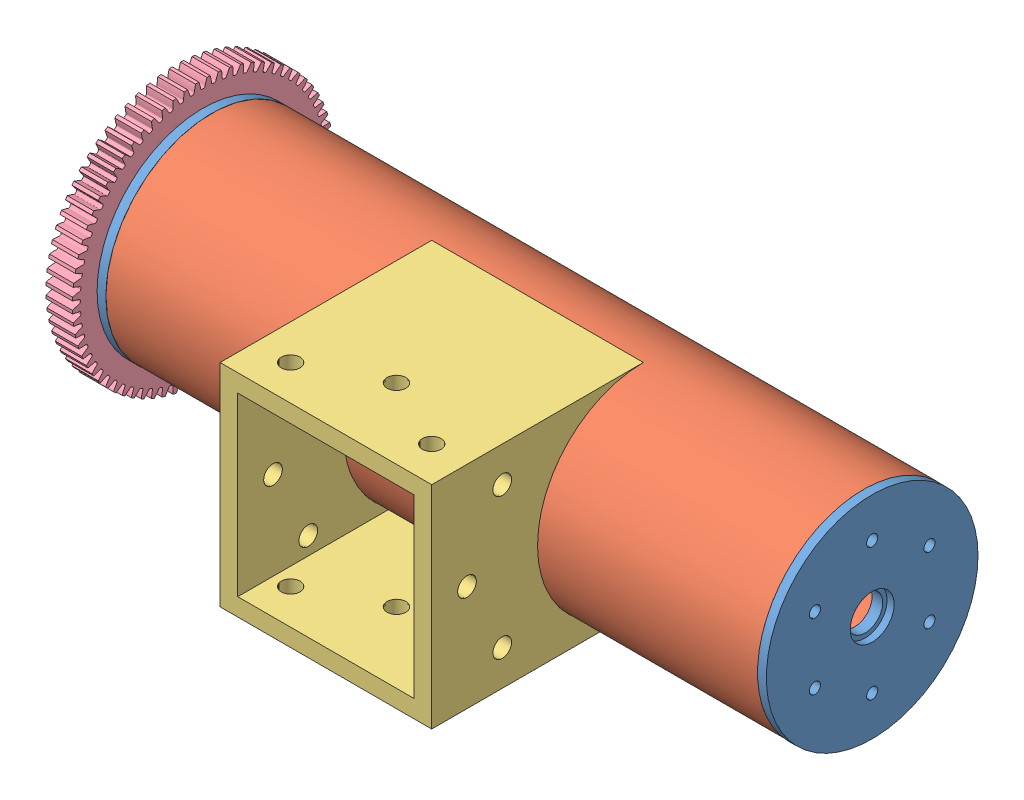
SolidWorks assembly 2018-303-A-1, configuration Default. Lengths in mm.
Overall size (252.08 94.86 123.63).
5 component instances, 4 part files, 11 mates.
Components (placement in the parent):
- 2018-303-D005-1: 2018-303-D005 [Default] at (9.1822 41.6905 65.6706) size (6.35 76.2 76.2)
- 2018-303-D002-1: 2018-303-D002 [Default] at (129.6798 41.6905 65.6706) x (1 0 0) z (0 0.972075 -0.234672) size (234.65 76.2 76.2)
- 2018-303-D005-2: 2018-303-D005 [Default] at (250.1774 41.6905 65.6706) x (-1 0 0) z (0 0 -1) size (6.35 76.2 76.2)
- 2018-303-D004-1: 2018-303-D004 [Default] at (91.5798 3.5905 65.6706) size (76.2 76.2 76.2)
- 72t_Aluminum_Spur_Gear_20_DP_1_2_Hex_Bore_VersaKeys_217-2716-1: 72t_Aluminum_Spur_Gear_20_DP_1_2_Hex_Bore_VersaKeys_217-2716 [Default] at (4.4197 41.6905 65.6706) x (0 0 1) z (-1 0 0) size (94.86 94.86 12.65)
Mates (geometry in assembly coordinates):
- Concentric1: concentric anti-aligned: cylinder of 2018-303-D005-1 through (12.3572 41.6905 65.6706) axis (1 0 0) radius 34.925; cylinder of 2018-303-D002-1 through (247.0024 41.6905 65.6706) axis (-1 0 0) radius 34.925
- Coincident1: coincident anti-aligned: plane of 2018-303-D005-1 through (12.3572 41.6905 65.6706) normal (1 0 0); plane of 2018-303-D002-1 through (12.3572 41.6905 65.6706) normal (-1 0 0)
- Concentric2: concentric aligned: cylinder of 2018-303-D002-1 through (247.0024 41.6905 65.6706) axis (-1 0 0) radius 34.925; cylinder of 2018-303-D005-2 through (247.0024 41.6905 65.6706) axis (-1 0 0) radius 34.925
- Coincident2: coincident anti-aligned: plane of 2018-303-D002-1 through (247.0024 41.6905 65.6706) normal (1 0 0); plane of 2018-303-D005-2 through (247.0024 41.6905 65.6706) normal (-1 0 0)
- Coincident3: coincident anti-aligned: plane of 2018-303-D005-1 through (9.1822 41.6905 65.6706) normal (0 0 1); plane of 2018-303-D005-2 through (250.1774 41.6905 65.6706) normal (0 0 -1)
- Concentric4: concentric anti-aligned: cylinder of 2018-303-D002-1 through (247.0024 41.6905 65.6706) axis (-1 0 0) radius 38.1; cylinder of 2018-303-D004-1 through (91.5798 41.6905 65.6706) axis (1 0 0) radius 38.1
- Parallel1: parallel aligned: plane of 2018-303-D004-1 through (91.5798 79.7905 141.8706) normal (0 1 0); plane of assembly through (0 0 0) normal (0 1 0)
- Coincident6: coincident anti-aligned: plane of 2018-303-D002-1 through (129.6798 41.6905 65.6706) normal (1 0 0); plane of 2018-303-D004-1 through (129.6798 3.5905 65.6706) normal (-1 0 0)
- Coincident7: coincident anti-aligned: plane of 2018-303-D005-1 through (9.1822 41.6905 65.6706) normal (-1 0 0); plane of 72t_Aluminum_Spur_Gear_20_DP_1_2_Hex_Bore_VersaKeys_217-2716-1 through (9.1822 88.6805 65.6706) normal (1 0 0)
- Concentric5: concentric aligned: cylinder of 2018-303-D005-1 through (9.1822 29.7843 45.0484) axis (-1 0 0) radius 2.0193; cylinder of 72t_Aluminum_Spur_Gear_20_DP_1_2_Hex_Bore_VersaKeys_217-2716-1 through (10.7443 29.7843 45.0484) axis (-1 0 0) radius 2.15
- Concentric6: concentric aligned: cylinder of 2018-303-D005-1 through (9.1822 53.5968 86.2928) axis (-1 0 0) radius 2.0193; cylinder of 72t_Aluminum_Spur_Gear_20_DP_1_2_Hex_Bore_VersaKeys_217-2716-1 through (10.7443 53.5968 86.2928) axis (-1 0 0) radius 2.15
